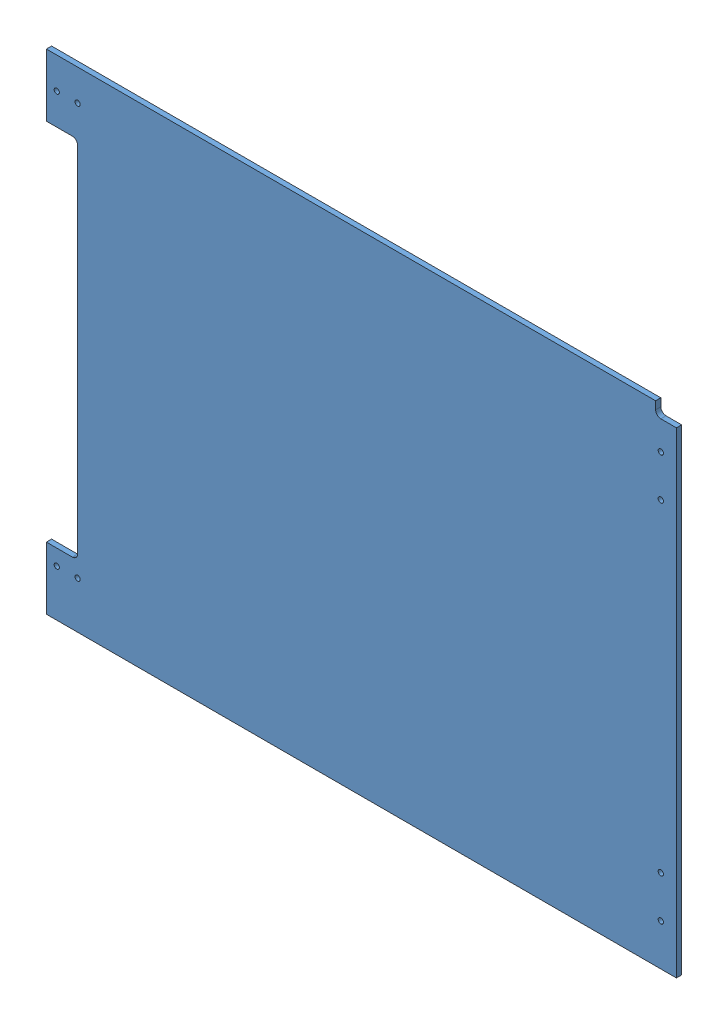
SolidWorks assembly GE-19079-Right-Blue, configuration Default. Lengths in mm.
Overall size (768.35 596.9 44.58).
2 component instances, 2 part files, 2 mates.
Components (placement in the parent):
- GE-19079-1: GE-19079 [GE-19079] at origin size (768.35 596.9 6.35)
- GE-19079-Right-Blue-Vinyl-1: GE-19079-Right-Blue-Vinyl [Notched] at (0 0 6.35) size (768.35 596.9 0.13)
Mates (geometry in assembly coordinates):
- Coincident1: coincident: plane of assembly; plane of assembly; plane of GE-19079-1 through (0 0 6.35) normal (0 0 1); plane of GE-19079-Right-Blue-Vinyl-1 through (0 0 6.35) normal (0 0 -1)
- Coincident2: coincident: plane of assembly; plane of assembly; plane of GE-19079-1 through (-400.05 298.45 -82.55) normal (-1 0 0); plane of GE-19079-Right-Blue-Vinyl-1 through (-400.05 298.45 -76.2) normal (-1 0 0)
